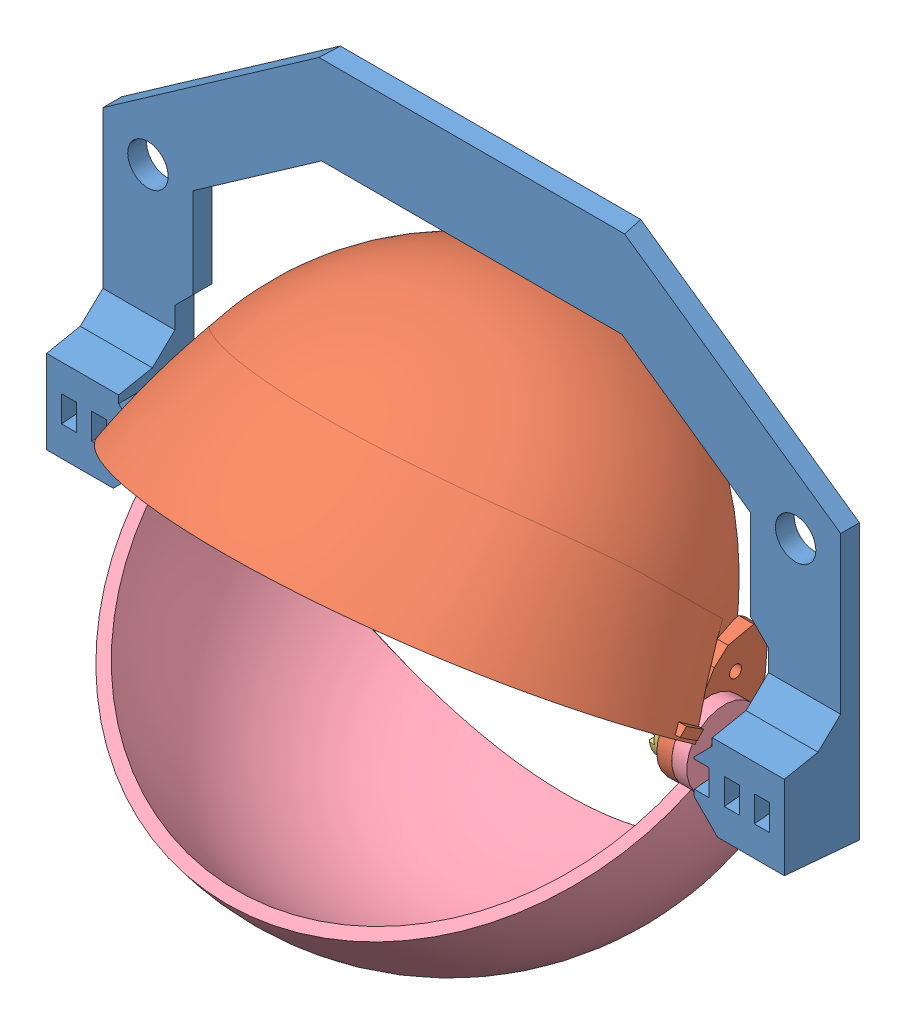
SolidWorks assembly Assembly_EyeLid, configuration Default. Lengths in mm.
Overall size (72.1 64.47 38.53).
5 component instances, 4 part files, 8 mates.
Components (placement in the parent):
- eyeLidMount_B-2: eyeLidMount_B [Default] at (1.4212 19.8823 -3.1275) size (62.38 36.2 5.33)
- eyelidBottomD-2: eyelidBottomD [Default] at (1.4974 -12.1217 0.0475) x (-1 0 0) z (0 -0.542705 -0.839924) size (51.87 24.77 27.68)
- shoulderScrew_2_56_1_8ths_shoulderLngth-3: shoulderScrew_2_56_1_8ths_shoulderLngth [99154A301] at (21.8174 -12.1217 0.0475) x (0 1 0) z (0 0 1) size (4.76 30.2 4.76)
- eyelidTopB-2: eyelidTopB [Default] at (1.1164 -12.1217 0.0475) x (1 0 0) z (0 0.587664 -0.809105) size (49.02 26.42 26.42)
- shoulderScrew_2_56_1_8ths_shoulderLngth-4: shoulderScrew_2_56_1_8ths_shoulderLngth [99154A301] at (-18.975 -12.1217 0.0475) x (0 -0.999956 0.009427) z (0 0.009427 0.999956) size (4.76 30.2 4.76)
Mates (geometry in assembly coordinates):
- Concentric5: concentric aligned: cylinder of eyeLidMount_B-2 through (26.2624 -12.1217 0.0475) axis (-1 0 0) radius 0.8255; cylinder of shoulderScrew_2_56_1_8ths_shoulderLngth-3 through (24.9924 -12.1217 0.0475) axis (-1 0 0) radius 1.1906
- Coincident5: coincident anti-aligned: plane of eyeLidMount_B-2 through (24.9924 -16.3127 3.2225) normal (-1 0 0); plane of shoulderScrew_2_56_1_8ths_shoulderLngth-3 through (24.9924 -12.1217 0.0475) normal (1 0 0)
- Coincident6: coincident anti-aligned: plane of eyelidBottomD-2 through (21.8174 -12.1217 0.0475) normal (-1 0 0); plane of shoulderScrew_2_56_1_8ths_shoulderLngth-3 through (21.8174 -12.1217 0.0475) normal (1 0 0)
- Coincident7: coincident anti-aligned: plane of eyelidBottomD-2 through (23.0874 -12.1217 0.0475) normal (1 0 0); plane of eyelidTopB-2 through (23.0874 -12.1217 0.0475) normal (-1 0 0)
- Concentric6: concentric aligned: cylinder of eyelidBottomD-2 through (23.0874 -12.1217 0.0475) axis (-1 0 0) radius 1.3335; cylinder of shoulderScrew_2_56_1_8ths_shoulderLngth-3 through (24.9924 -12.1217 0.0475) axis (-1 0 0) radius 1.1906
- Concentric7: concentric anti-aligned: cylinder of shoulderScrew_2_56_1_8ths_shoulderLngth-3 through (24.9924 -12.1217 0.0475) axis (-1 0 0) radius 1.1906; cylinder of eyelidTopB-2 through (-22.1246 -12.1217 0.0475) axis (1 0 0) radius 1.3335
- Concentric8: concentric aligned: cylinder of eyeLidMount_B-2 through (-23.42 -12.1217 0.0475) axis (1 0 0) radius 0.8255; cylinder of shoulderScrew_2_56_1_8ths_shoulderLngth-4 through (-22.15 -12.1217 0.0475) axis (1 0 0) radius 1.1906
- Coincident8: coincident anti-aligned: plane of eyeLidMount_B-2 through (-22.15 -16.3127 3.2225) normal (1 0 0); plane of shoulderScrew_2_56_1_8ths_shoulderLngth-4 through (-22.15 -12.1217 0.0475) normal (-1 0 0)
